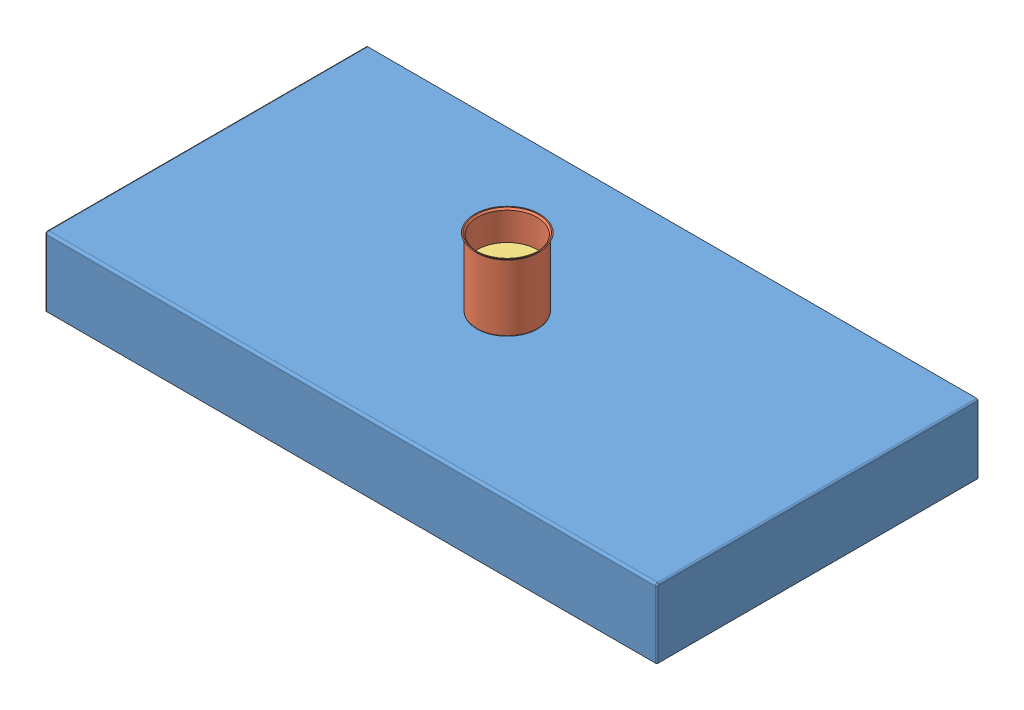
SolidWorks assembly Teste, configuration Valor predeterminado. Lengths in mm.
Overall size (800 179.33 420).
3 component instances, 3 part files, 0 mates.
Components (placement in the parent):
- mesa-1: mesa [Valor predeterminado] at (-14.2223 -84.1731 0) size (800 90 420)
- becker_maior-1: becker_maior [Valor predeterminado] at (-21.0983 -1.1967 -1.2512) size (84.86 90 84.86)
- liquido_teste-1: liquido_teste [Valor predeterminado] at (11.1485 -61.0708 19.6443) size (78 50.4 78)
